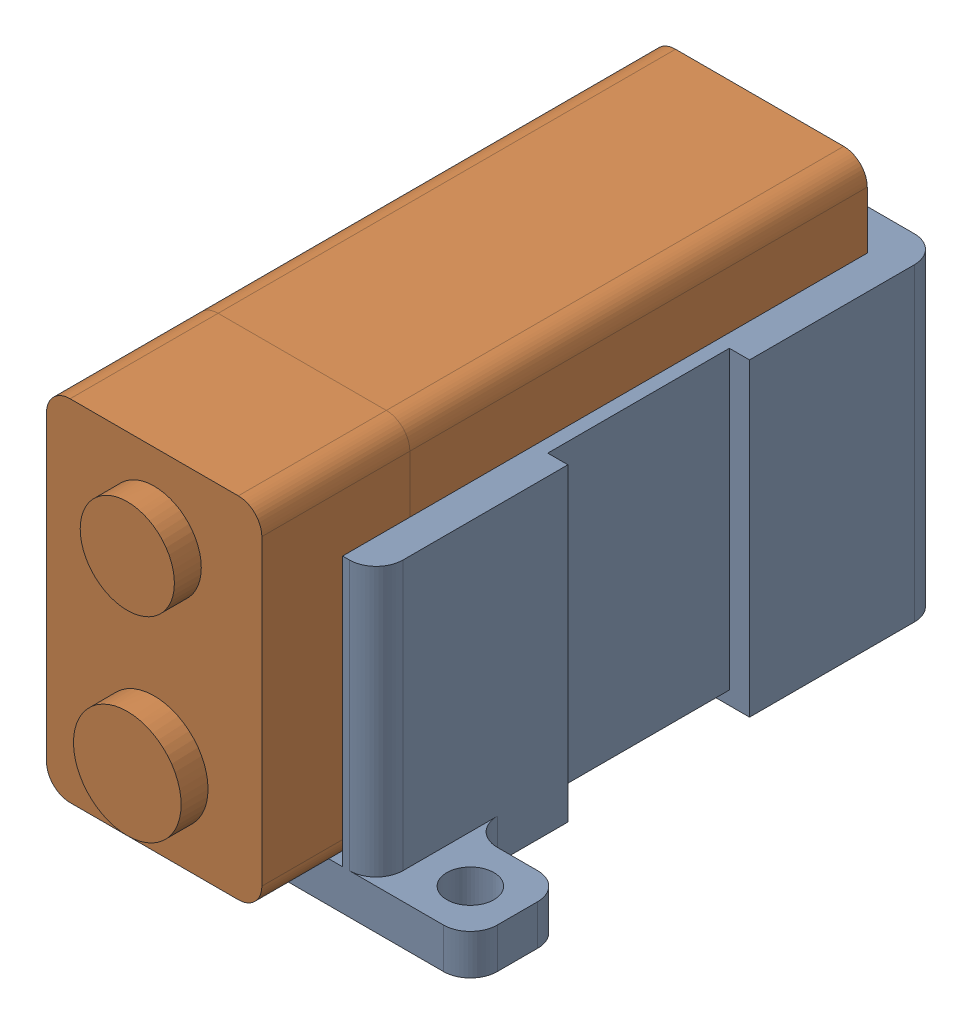
SolidWorks assembly 9VAssembly, configuration Default. Lengths in mm.
Overall size (28.8 29 57).
2 component instances, 2 part files, 6 mates.
Components (placement in the parent):
- 9VBatteryMount_rev5-1: 9VBatteryMount_rev5 [Default] at (30.4 0 -9) x (0 0 -1) z (1 0 0) size (49 23 28.8)
- 9VBattery-1: 9VBattery [Default] at (11.3 16 -39) x (0 -1 0) z (-1 0 0) size (26 47 16)
Mates (geometry in assembly coordinates):
- Coincident1: coincident anti-aligned: plane of 9VBatteryMount_rev5-1 through (-30.3115 0 -9) normal (0 -1 0)
- Coincident2: coincident aligned: plane of 9VBatteryMount_rev5-1 through (-30.3115 3 0) normal (0 0 1)
- Coincident3: coincident anti-aligned: plane of 9VBatteryMount_rev5-1 through (0 3 -9) normal (-1 0 0)
- Coincident4: coincident: plane of 9VBattery-1 through (11.3 16 -39) normal (0 0 -1); plane of 9VBatteryMount_rev5-1 through (30.4 23 -39) normal (0 0 1)
- Coincident5: coincident: plane of 9VBatteryMount_rev5-1 through (30.4 3 -9) normal (0 1 0); plane of 9VBattery-1 through (3.3 3 6) normal (0 -1 0)
- Coincident6: coincident anti-aligned: plane of 9VBatteryMount_rev5-1 through (19.3 23 -9) normal (-1 0 0); plane of 9VBattery-1 through (19.3 29 6) normal (1 0 0)
